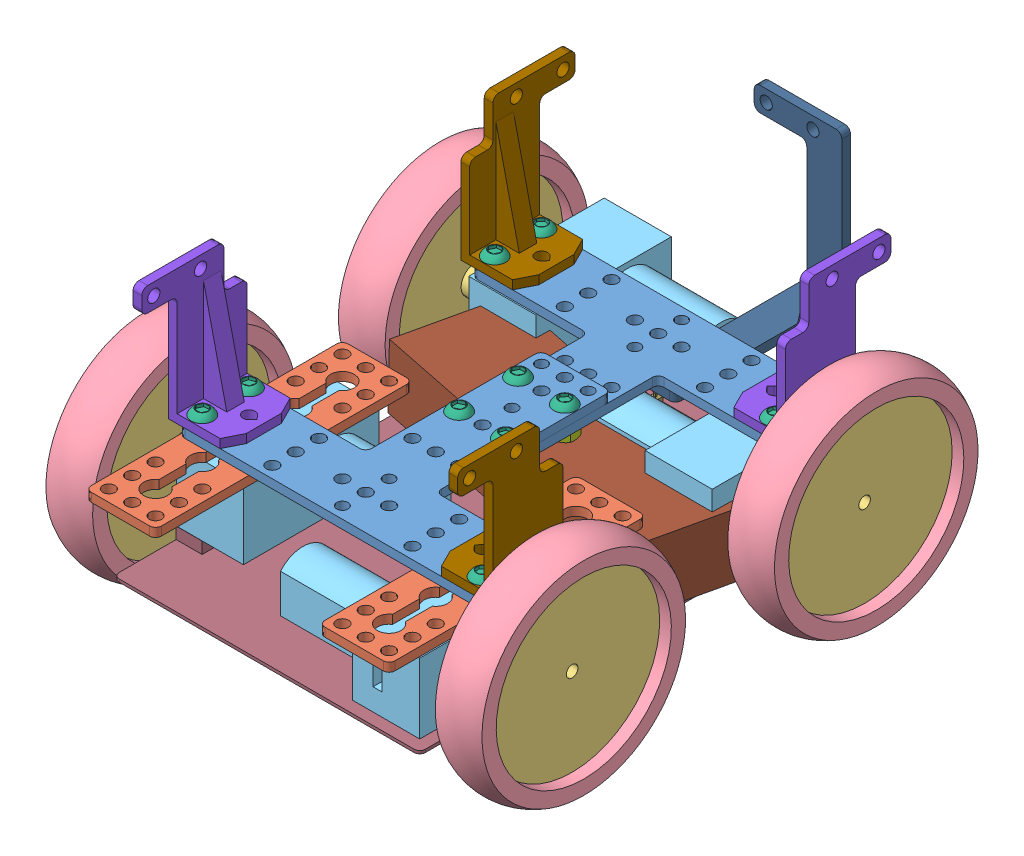
SolidWorks assembly robot_asm, configuration Default. Lengths in mm.
Overall size (148.9 115.69 200.04).
51 component instances, 19 part files, 120 mates.
Components (placement in the parent):
- maze-2: maze [Default] at origin size (310 310 586.12) (hidden)
  - maze_cell-1: maze_cell [Default] at origin size (310 310 310)
  - maze_slope-1: maze_slope [Default] at (0 -9.0631 4.2262) x (0 0.422618 0.906308) z (-1 0 0) size (300 10 300)
- T-bracket-1: T-bracket [Default] at (150 49 -175.7799) size (104 3 84)
- T-bracket-2: T-bracket [Default] at (150 52 -99.5799) x (-1 0 0) z (0 0 -1) size (104 3 84)
- bracket-1: bracket [Default] at (98 49 -43.5799) size (24 3 88)
- bracket-3: bracket [Default] at (178 49 -43.5799) size (24 3 88)
- wheels-1: wheels [Default] at (87.55 37 -87.3299) x (0 0 1) z (-1 0 0) size (67.99 67.99 16)
- wheels-2: wheels [Default] at (87.55 37 -187.5299) x (0 0 -1) z (-1 0 0) size (67.99 67.99 16)
- wheels-4: wheels [Default] at (212.45 37 -188.0299) x (0 0 1) z (1 0 0) size (67.99 67.99 16)
- wheels-6: wheels [Default] at (212.45 37 -87.8299) x (0 0 1) z (1 0 0) size (67.99 67.99 16)
- tire-1: tire [Default] at (216.45 37 -87.8299) x (1 0 0) z (0 0.015779 -0.999876) size (16 74 74)
- tire-2: tire [Default] at (216.45 37 -188.0299) x (1 0 0) z (0 0.008537 -0.999964) size (16 74 74)
- tire-4: tire [Default] at (83.55 37 -187.5299) x (-1 0 0) z (0 -0.999272 0.038138) size (16 74 74)
- tire-6: tire [Default] at (83.55 37 -87.3299) x (-1 0 0) z (0 -0.815244 0.579117) size (16 74 74)
- encoder_motor-1: encoder_motor [Default] at (97.55 37 -221.7299) x (1 0 0) z (0 -1 0) size (64 46.4 24)
- encoder_motor-2: encoder_motor [Default] at (202.45 37 -153.8299) x (-1 0 0) z (0 -1 0) size (64 46.4 24)
- encoder_motor-5: encoder_motor [Default] at (97.55 37 -121.5299) x (1 0 0) z (0 -1 0) size (64 46.4 24)
- encoder_motor-7: encoder_motor [Default] at (202.45 37 -53.6299) x (-1 0 0) z (0 -1 0) size (64 46.4 24)
- auriga_board-1: auriga_board [Default] at (150 55 -228.2799) x (-1 0 0) z (0 0 -1) size (88.1 25.8 109.5) (hidden)
- raspberrypi_4-1: raspberrypi_4 [Default] at (181.9914 89.0117 -123.3645) x (0.017452 0 -0.999848) z (0.999848 0 0.017452) size (88 17.5 57.5) (hidden)
- bigscrew-6: bigscrew [Default] at (158 45 -147.7799) x (0.646317 0 -0.763069) z (0.763069 0 0.646317) size (7.5 12 7.5)
- bigscrew-8: bigscrew [Default] at (142 45 -147.7799) x (0.458424 0 -0.888734) z (0.888734 0 0.458424) size (7.5 12 7.5)
- bigscrew-10: bigscrew [Default] at (158 45 -127.5799) x (0.282723 0 -0.959201) z (0.959201 0 0.282723) size (7.5 12 7.5)
- bigscrew-11: bigscrew [Default] at (142 45 -127.5799) x (0.069298 0 -0.997596) z (0.997596 0 0.069298) size (7.5 12 7.5)
- bigscrew-12: bigscrew [Default] at (198 48 -79.5799) x (-0.166501 0 -0.986041) z (0.986041 0 -0.166501) size (7.5 12 7.5)
- bigscrew-13: bigscrew [Default] at (198 48 -95.5799) x (-0.397145 0 -0.917756) z (0.917756 0 -0.397145) size (7.5 12 7.5)
- bigscrew-14: bigscrew [Default] at (102 48 -79.5799) x (-0.593123 0 -0.805112) z (0.805112 0 -0.593123) size (7.5 12 7.5)
- bigscrew-15: bigscrew [Default] at (102 48 -95.5799) x (-0.736724 0 -0.676194) z (0.676194 0 -0.736724) size (7.5 12 7.5)
- nut-1: nut [Default] at (158 47.5 -127.5799) x (0.999863 0 0.016576) z (-0.016576 0 0.999863) size (8.21 3.51 7.16)
- nut-2: nut [Default] at (142 47.5 -127.5799) x (0.985071 0 -0.17215) z (0.17215 0 0.985071) size (8.21 3.51 7.16)
- nut-3: nut [Default] at (142 47.5 -147.7799) x (0.924799 0 -0.380457) z (0.380457 0 0.924799) size (8.21 3.51 7.16)
- nut-4: nut [Default] at (158 47.5 -147.7799) x (0.809836 0 -0.586657) z (0.586657 0 0.809836) size (8.21 3.51 7.16)
- bigscrew-20: bigscrew [Default] at (102 45 -195.7799) x (-0.349342 0 -0.936995) z (0.936995 0 -0.349342) size (7.5 12 7.5)
- bigscrew-21: bigscrew [Default] at (102 45 -179.7799) x (-0.562985 0 -0.826467) z (0.826467 0 -0.562985) size (7.5 12 7.5)
- bigscrew-24: bigscrew [Default] at (198 45 -195.7799) x (-0.734222 0 -0.678909) z (0.678909 0 -0.734222) size (7.5 12 7.5)
- bigscrew-25: bigscrew [Default] at (198 45 -179.7799) x (-0.850955 0 -0.525238) z (0.525238 0 -0.850955) size (7.5 12 7.5)
- ultrasonic_bracket_left-1: ultrasonic_bracket_left [Default] at (97.4 55 -87.5799) x (0 0 -1) z (1 0 0) size (36.1 46.1 20.7)
- ultrasonic_bracket_right-1: ultrasonic_bracket_right [Default] at (202.6 55 -87.5799) x (0 0 -1) z (1 0 0) size (36.1 46.1 20.7)
- ultrasonic_bracket_right-4: ultrasonic_bracket_right [Default] at (97.4 52 -187.7799) x (0 0 1) z (-1 0 0) size (36.1 46.1 20.7)
- ultrasonic_bracket_left-2: ultrasonic_bracket_left [Default] at (202.6 52 -187.7799) x (0 0 1) z (-1 0 0) size (36.1 46.1 20.7)
- ultrasonic_bracket_front-1: ultrasonic_bracket_front [Default] at (161.9 46 -232.7799) size (30 52.1 60)
- ultrasonic_sensor-1: ultrasonic_sensor [Default] at (201.1 93 -75.5799) x (0 0 -1) z (0 -1 0) size (56 29.8 36) (hidden)
- ultrasonic_sensor-3: ultrasonic_sensor [Default] at (150 90 -231.2799) x (-1 0 0) z (0 -1 0) size (56 29.8 36) (hidden)
- ultrasonic_sensor-4: ultrasonic_sensor [Default] at (98.9 93 -75.5799) x (0 0 1) z (0 -1 0) size (56 29.8 36) (hidden)
- ultrasonic_sensor-7: ultrasonic_sensor [Default] at (98.9 90 -199.7799) x (0 0 1) z (0 -1 0) size (56 29.8 36) (hidden)
- ultrasonic_sensor-9: ultrasonic_sensor [Default] at (201.1 90 -199.7799) x (0 0 -1) z (0 -1 0) size (56 29.8 36) (hidden)
- battery-1: battery [Default] at (99.7426 20.6883 -166.1374) x (-0.199339 0.017452 0.979775) z (-0.979925 -0.000152 -0.199367) size (35 21.7 105)
- picamera-1: picamera [Default] at (104.6974 75.4836 -152.1545) x (-0.008727 0 0.999962) z (-0.008726 -0.999962 -0.000076) size (361.94 309 272.17) (hidden)
- coloursensor-1: coloursensor [Default] at (140.094 21 -197.6859) x (0 0 1) z (-1 0 0) size (20.32 7.03 26.3)
- undercover-1: undercover [Default] at (202.45 25 -153.8299) x (-1 0 0) z (0 -1 0) size (104.9 168.1 5)
Mates (geometry in assembly coordinates):
- Concentric1: concentric aligned: cylinder of T-bracket-1 through (142 49 -147.7799) axis (0 1 0) radius 2.1; cylinder of T-bracket-2 through (142 52 -147.7799) axis (0 1 0) radius 2.1
- Concentric2: concentric aligned: cylinder of T-bracket-1 through (158 49 -127.5799) axis (0 1 0) radius 2.1; cylinder of T-bracket-2 through (158 52 -127.5799) axis (0 1 0) radius 2.1
- Coincident1: coincident anti-aligned: plane of T-bracket-1 through (150 52 -175.7799) normal (0 1 0); plane of T-bracket-2 through (150 52 -99.5799) normal (0 -1 0)
- Concentric5: concentric aligned: cylinder of T-bracket-1 through (102 49 -195.7799) axis (0 1 0) radius 2.1; cylinder of encoder_motor-1 through (102 43.5 -195.7799) axis (0 1 0) radius 1.95
- Concentric6: concentric aligned: cylinder of T-bracket-1 through (102 49 -179.7799) axis (0 1 0) radius 2.1; cylinder of encoder_motor-1 through (102 43.5 -179.7799) axis (0 1 0) radius 1.95
- Coincident3: coincident anti-aligned: plane of T-bracket-1 through (150 49 -175.7799) normal (0 -1 0); plane of encoder_motor-1 through (97.55 49 -221.7299) normal (0 1 0)
- Concentric7: concentric aligned: cylinder of T-bracket-1 through (198 49 -179.7799) axis (0 1 0) radius 2.1; cylinder of encoder_motor-2 through (198 43.5 -179.7799) axis (0 1 0) radius 1.95
- Concentric8: concentric aligned: cylinder of T-bracket-1 through (198 49 -195.7799) axis (0 1 0) radius 2.1; cylinder of encoder_motor-2 through (198 43.5 -195.7799) axis (0 1 0) radius 1.95
- Coincident4: coincident anti-aligned: plane of T-bracket-1 through (150 49 -175.7799) normal (0 -1 0); plane of encoder_motor-2 through (202.45 49 -153.8299) normal (0 1 0)
- Concentric11: concentric aligned: cylinder of T-bracket-2 through (102 52 -95.5799) axis (0 1 0) radius 2.1; cylinder of bracket-1 through (102 49 -95.5799) axis (0 1 0) radius 2.1
- Concentric12: concentric aligned: cylinder of T-bracket-2 through (102 52 -79.5799) axis (0 1 0) radius 2.1; cylinder of bracket-1 through (102 49 -79.5799) axis (0 1 0) radius 2.1
- Coincident6: coincident anti-aligned: plane of T-bracket-2 through (150 52 -99.5799) normal (0 -1 0); plane of bracket-1 through (98 52 -43.5799) normal (0 1 0)
- Concentric13: concentric aligned: cylinder of T-bracket-2 through (198 52 -95.5799) axis (0 1 0) radius 2.1; cylinder of bracket-3 through (198 49 -95.5799) axis (0 1 0) radius 2.1
- Concentric14: concentric aligned: cylinder of T-bracket-2 through (198 52 -79.5799) axis (0 1 0) radius 2.1; cylinder of bracket-3 through (198 49 -79.5799) axis (0 1 0) radius 2.1
- Coincident7: coincident anti-aligned: plane of T-bracket-2 through (150 52 -99.5799) normal (0 -1 0); plane of bracket-3 through (178 52 -43.5799) normal (0 1 0)
- Concentric15: concentric aligned: cylinder of T-bracket-2 through (102 52 -95.5799) axis (0 1 0) radius 2.1; cylinder of encoder_motor-5 through (102 43.5 -95.5799) axis (0 1 0) radius 1.95
- Concentric16: concentric aligned: cylinder of T-bracket-2 through (102 52 -79.5799) axis (0 1 0) radius 2.1; cylinder of encoder_motor-5 through (102 43.5 -79.5799) axis (0 1 0) radius 1.95
- Coincident8: coincident anti-aligned: plane of bracket-1 through (98 49 -43.5799) normal (0 -1 0); plane of encoder_motor-5 through (97.55 49 -121.5299) normal (0 1 0)
- Concentric17: concentric aligned: cylinder of T-bracket-2 through (198 52 -79.5799) axis (0 1 0) radius 2.1; cylinder of encoder_motor-7 through (198 43.5 -79.5799) axis (0 1 0) radius 1.95
- Concentric18: concentric aligned: cylinder of T-bracket-2 through (198 52 -95.5799) axis (0 1 0) radius 2.1; cylinder of encoder_motor-7 through (198 43.5 -95.5799) axis (0 1 0) radius 1.95
- Coincident9: coincident anti-aligned: plane of bracket-3 through (178 49 -43.5799) normal (0 -1 0); plane of encoder_motor-7 through (202.45 49 -53.6299) normal (0 1 0)
- Concentric19: concentric aligned: cylinder of encoder_motor-5 through (88.55 37 -87.3299) axis (1 0 0) radius 2.7; cylinder of wheels-1 through (81.1435 37 -87.3299) axis (1 0 0) radius 2.85
- Parallel1: parallel anti-aligned: plane of encoder_motor-5 through (88.55 35.25 -75.1299) normal (0 -1 0); plane of wheels-1 through (81.1435 35.05 -85.2514) normal (0 1 0)
- Coincident11: coincident anti-aligned: plane of encoder_motor-5 through (95.55 35.25 -75.1299) normal (-1 0 0); plane of wheels-1 through (95.55 37 -87.3299) normal (1 0 0)
- Concentric20: concentric aligned: cylinder of encoder_motor-1 through (88.55 37 -187.5299) axis (1 0 0) radius 2.7; cylinder of wheels-2 through (81.1435 37 -187.5299) axis (1 0 0) radius 2.85
- Parallel2: parallel anti-aligned: plane of encoder_motor-1 through (88.55 38.75 -175.3299) normal (0 1 0); plane of wheels-2 through (81.1435 38.95 -189.6084) normal (0 -1 0)
- Coincident12: coincident anti-aligned: plane of encoder_motor-1 through (95.55 38.75 -175.3299) normal (-1 0 0); plane of wheels-2 through (95.55 37 -187.5299) normal (1 0 0)
- Concentric21: concentric aligned: cylinder of encoder_motor-2 through (211.45 37 -188.0299) axis (-1 0 0) radius 2.7; cylinder of wheels-4 through (218.8565 37 -188.0299) axis (-1 0 0) radius 2.85
- Parallel3: parallel anti-aligned: plane of encoder_motor-2 through (211.45 38.75 -200.2299) normal (0 1 0); plane of wheels-4 through (218.8565 38.95 -185.9514) normal (0 -1 0)
- Coincident13: coincident anti-aligned: plane of encoder_motor-2 through (204.45 38.75 -200.2299) normal (1 0 0); plane of wheels-4 through (204.45 37 -188.0299) normal (-1 0 0)
- Concentric22: concentric aligned: cylinder of encoder_motor-7 through (211.45 37 -87.8299) axis (-1 0 0) radius 2.7; cylinder of wheels-6 through (218.8565 37 -87.8299) axis (-1 0 0) radius 2.85
- Parallel4: parallel anti-aligned: plane of encoder_motor-7 through (211.45 38.75 -100.0299) normal (0 1 0); plane of wheels-6 through (218.8565 38.95 -85.7514) normal (0 -1 0)
- Coincident14: coincident anti-aligned: plane of encoder_motor-7 through (204.45 38.75 -100.0299) normal (1 0 0); plane of wheels-6 through (204.45 37 -87.8299) normal (-1 0 0)
- Concentric23: concentric aligned: cylinder of wheels-6 through (220.45 37 -87.8299) axis (-1 0 0) radius 34; cylinder of tire-1 through (-474.0168 37 -87.8299) axis (-1 0 0) radius 33
- Coincident16: coincident anti-aligned: plane of wheels-6 through (212.45 37 -87.8299) normal (-1 0 0); plane of tire-1 through (212.45 4.0041 -88.3506) normal (1 0 0)
- Concentric24: concentric aligned: cylinder of wheels-4 through (220.45 37 -188.0299) axis (-1 0 0) radius 34; cylinder of tire-2 through (-474.0168 37 -188.0299) axis (-1 0 0) radius 33
- Coincident17: coincident anti-aligned: plane of wheels-4 through (212.45 37 -188.0299) normal (-1 0 0); plane of tire-2 through (212.45 4.0012 -188.3116) normal (1 0 0)
- Concentric25: concentric aligned: cylinder of wheels-2 through (79.55 37 -187.5299) axis (1 0 0) radius 34; cylinder of tire-4 through (774.0168 37 -187.5299) axis (1 0 0) radius 33
- Coincident18: coincident anti-aligned: plane of wheels-2 through (87.55 37 -187.5299) normal (1 0 0); plane of tire-4 through (87.55 35.7414 -220.5059) normal (-1 0 0)
- Concentric26: concentric aligned: cylinder of wheels-1 through (79.55 37 -87.3299) axis (1 0 0) radius 34; cylinder of tire-6 through (774.0168 37 -87.3299) axis (1 0 0) radius 33
- Coincident19: coincident anti-aligned: plane of wheels-1 through (87.55 37 -87.3299) normal (1 0 0); plane of tire-6 through (87.55 17.8891 -114.233) normal (-1 0 0)
- Coincident25: coincident anti-aligned: plane of T-bracket-2 through (150 55 -99.5799) normal (0 1 0); plane of bigscrew-6 through (159.2926 55 -149.306) normal (0 -1 0)
- Concentric31: concentric anti-aligned: cylinder of T-bracket-2 through (158 52 -147.7799) axis (0 1 0) radius 2.1; cylinder of bigscrew-6 through (158 -265.2059 -147.7799) axis (0 -1 0) radius 2
- Concentric32: concentric anti-aligned: cylinder of T-bracket-2 through (142 52 -147.7799) axis (0 1 0) radius 2.1; cylinder of bigscrew-8 through (142 -265.2059 -147.7799) axis (0 -1 0) radius 2
- Coincident27: coincident anti-aligned: plane of T-bracket-2 through (150 55 -99.5799) normal (0 1 0); plane of bigscrew-8 through (142.9168 55 -149.5574) normal (0 -1 0)
- Coincident28: coincident anti-aligned: plane of T-bracket-2 through (150 55 -99.5799) normal (0 1 0); plane of bigscrew-10 through (158.5654 55 -129.4983) normal (0 -1 0)
- Concentric33: concentric anti-aligned: cylinder of T-bracket-2 through (158 52 -127.5799) axis (0 1 0) radius 2.1; cylinder of bigscrew-10 through (158 -265.2059 -127.5799) axis (0 -1 0) radius 2
- Coincident29: coincident anti-aligned: plane of T-bracket-2 through (150 55 -99.5799) normal (0 1 0); plane of bigscrew-11 through (142.1386 55 -129.5751) normal (0 -1 0)
- Concentric34: concentric anti-aligned: cylinder of T-bracket-2 through (142 52 -127.5799) axis (0 1 0) radius 2.1; cylinder of bigscrew-11 through (142 -265.2059 -127.5799) axis (0 -1 0) radius 2
- Coincident30: coincident anti-aligned: plane of ultrasonic_bracket_right-1 through (202.6 58 -87.5799) normal (0 1 0); plane of bigscrew-12 through (197.667 58 -81.552) normal (0 -1 0)
- Concentric35: concentric anti-aligned: cylinder of T-bracket-2 through (198 52 -79.5799) axis (0 1 0) radius 2.1; cylinder of bigscrew-12 through (198 -262.2059 -79.5799) axis (0 -1 0) radius 2
- Coincident31: coincident anti-aligned: plane of ultrasonic_bracket_right-1 through (202.6 58 -87.5799) normal (0 1 0); plane of bigscrew-13 through (197.2057 58 -97.4154) normal (0 -1 0)
- Concentric36: concentric anti-aligned: cylinder of T-bracket-2 through (198 52 -95.5799) axis (0 1 0) radius 2.1; cylinder of bigscrew-13 through (198 -262.2059 -95.5799) axis (0 -1 0) radius 2
- Concentric37: concentric anti-aligned: cylinder of T-bracket-2 through (102 52 -79.5799) axis (0 1 0) radius 2.1; cylinder of bigscrew-14 through (102 -262.2059 -79.5799) axis (0 -1 0) radius 2
- Concentric38: concentric anti-aligned: cylinder of T-bracket-2 through (102 52 -95.5799) axis (0 1 0) radius 2.1; cylinder of bigscrew-15 through (102 -262.2059 -95.5799) axis (0 -1 0) radius 2
- Concentric39: concentric aligned: cylinder of bigscrew-10 through (158 -265.2059 -127.5799) axis (0 -1 0) radius 2; cylinder of nut-1 through (158 49 -127.5799) axis (0 -1 0) radius 2
- Coincident35: coincident anti-aligned: plane of T-bracket-1 through (150 49 -175.7799) normal (0 -1 0); plane of nut-1 through (158 49 -127.5799) normal (0 1 0)
- Coincident36: coincident anti-aligned: plane of T-bracket-1 through (150 49 -175.7799) normal (0 -1 0); plane of nut-2 through (142 49 -127.5799) normal (0 1 0)
- Concentric40: concentric aligned: cylinder of bigscrew-11 through (142 -265.2059 -127.5799) axis (0 -1 0) radius 2; cylinder of nut-2 through (142 49 -127.5799) axis (0 -1 0) radius 2
- Coincident37: coincident anti-aligned: plane of T-bracket-1 through (150 49 -175.7799) normal (0 -1 0); plane of nut-3 through (142 49 -147.7799) normal (0 1 0)
- Concentric41: concentric aligned: cylinder of bigscrew-8 through (142 -265.2059 -147.7799) axis (0 -1 0) radius 2; cylinder of nut-3 through (142 49 -147.7799) axis (0 -1 0) radius 2
- Coincident38: coincident anti-aligned: plane of T-bracket-1 through (150 49 -175.7799) normal (0 -1 0); plane of nut-4 through (158 49 -147.7799) normal (0 1 0)
- Concentric42: concentric aligned: cylinder of bigscrew-6 through (158 -265.2059 -147.7799) axis (0 -1 0) radius 2; cylinder of nut-4 through (158 49 -147.7799) axis (0 -1 0) radius 2
- Tangent1: tangent anti-aligned: torus of tire-4; plane of maze-2/maze_cell-1 through (0 0 0) normal (0 1 0)
- Tangent4: tangent anti-aligned: plane of maze-2/maze_slope-1 through (0 0 0) normal (0 0.906308 -0.422618); torus of tire-1
- Tangent6: tangent anti-aligned: plane of maze-2/maze_cell-1 through (0 0 0) normal (0 1 0); torus of tire-2
- Tangent7: tangent anti-aligned: plane of maze-2/maze_slope-1 through (0 0 0) normal (0 0.906308 -0.422618); torus of tire-6
- Tangent8: tangent anti-aligned: plane of maze-2/maze_cell-1 through (0 0 0) normal (0 1 0); torus of tire-1
- Parallel7: parallel aligned: plane of maze-2/maze_cell-1 through (300 -10 0) normal (1 0 0); plane of wheels-6 through (220.45 37 -87.8299) normal (1 0 0)
- Distance1: distance = 150 mm: cylinder of T-bracket-2 through (150 52 -87.5799) axis (0 1 0) radius 2.1; plane of maze-2/maze_cell-1 through (0 0 0) normal (1 0 0)
- Concentric43: concentric anti-aligned: cylinder of T-bracket-2 through (102 52 -79.5799) axis (0 1 0) radius 2.1; cylinder of ultrasonic_bracket_left-1 through (102 58 -79.5799) axis (0 -1 0) radius 2.1
- Concentric44: concentric anti-aligned: cylinder of T-bracket-2 through (102 52 -95.5799) axis (0 1 0) radius 2.1; cylinder of ultrasonic_bracket_left-1 through (102 58 -95.5799) axis (0 -1 0) radius 2.1
- Coincident39: coincident anti-aligned: plane of T-bracket-2 through (150 55 -99.5799) normal (0 1 0); plane of ultrasonic_bracket_left-1 through (97.4 55 -87.5799) normal (0 -1 0)
- Coincident40: coincident anti-aligned: plane of bigscrew-14 through (100.8138 58 -81.1901) normal (0 -1 0); plane of ultrasonic_bracket_left-1 through (97.4 58 -87.5799) normal (0 1 0)
- Coincident41: coincident anti-aligned: plane of bigscrew-15 through (100.5266 58 -96.9323) normal (0 -1 0); plane of ultrasonic_bracket_left-1 through (97.4 58 -87.5799) normal (0 1 0)
- Concentric45: concentric aligned: cylinder of ultrasonic_sensor-4 through (97.4 97 -83.5799) axis (1 0 0) radius 2.1; cylinder of ultrasonic_bracket_left-1 through (94.4 97 -83.5799) axis (1 0 0) radius 2.1
- Concentric46: concentric aligned: cylinder of ultrasonic_sensor-4 through (97.4 97 -67.5799) axis (1 0 0) radius 2.1; cylinder of ultrasonic_bracket_left-1 through (94.4 97 -67.5799) axis (1 0 0) radius 2.1
- Coincident43: coincident anti-aligned: plane of ultrasonic_sensor-4 through (97.4 93 -75.5799) normal (-1 0 0); plane of ultrasonic_bracket_left-1 through (97.4 55 -87.5799) normal (1 0 0)
- Concentric47: concentric anti-aligned: cylinder of T-bracket-2 through (198 52 -95.5799) axis (0 1 0) radius 2.1; cylinder of ultrasonic_bracket_right-1 through (198 58 -95.5799) axis (0 -1 0) radius 2.1
- Concentric48: concentric anti-aligned: cylinder of T-bracket-2 through (198 52 -79.5799) axis (0 1 0) radius 2.1; cylinder of ultrasonic_bracket_right-1 through (198 58 -79.5799) axis (0 -1 0) radius 2.1
- Coincident45: coincident anti-aligned: plane of T-bracket-2 through (150 55 -99.5799) normal (0 1 0); plane of ultrasonic_bracket_right-1 through (202.6 55 -87.5799) normal (0 -1 0)
- Concentric49: concentric aligned: cylinder of ultrasonic_sensor-1 through (202.6 97 -83.5799) axis (-1 0 0) radius 2.1; cylinder of ultrasonic_bracket_right-1 through (205.6 97 -83.5799) axis (-1 0 0) radius 2.1
- Concentric50: concentric aligned: cylinder of ultrasonic_sensor-1 through (202.6 97 -67.5799) axis (-1 0 0) radius 2.1; cylinder of ultrasonic_bracket_right-1 through (205.6 97 -67.5799) axis (-1 0 0) radius 2.1
- Coincident46: coincident anti-aligned: plane of ultrasonic_sensor-1 through (202.6 93 -75.5799) normal (1 0 0); plane of ultrasonic_bracket_right-1 through (202.6 55 -87.5799) normal (-1 0 0)
- Coincident54: coincident anti-aligned: plane of ultrasonic_bracket_right-4 through (97.4 55 -187.7799) normal (0 1 0); plane of bigscrew-20 through (101.3013 55 -197.6539) normal (0 -1 0)
- Coincident55: coincident anti-aligned: plane of ultrasonic_bracket_right-4 through (97.4 55 -187.7799) normal (0 1 0); plane of bigscrew-21 through (100.874 55 -181.4328) normal (0 -1 0)
- Concentric61: concentric aligned: cylinder of ultrasonic_bracket_right-4 through (94.4 94 -191.7799) axis (1 0 0) radius 2.1; cylinder of ultrasonic_sensor-7 through (97.4 94 -191.7799) axis (1 0 0) radius 2.1
- Concentric62: concentric aligned: cylinder of ultrasonic_bracket_right-4 through (94.4 94 -207.7799) axis (1 0 0) radius 2.1; cylinder of ultrasonic_sensor-7 through (97.4 94 -207.7799) axis (1 0 0) radius 2.1
- Coincident56: coincident anti-aligned: plane of ultrasonic_bracket_right-4 through (97.4 52 -187.7799) normal (1 0 0); plane of ultrasonic_sensor-7 through (97.4 90 -199.7799) normal (-1 0 0)
- Concentric63: concentric anti-aligned: cylinder of T-bracket-1 through (102 49 -195.7799) axis (0 1 0) radius 2.1; cylinder of bigscrew-20 through (102 -265.2059 -195.7799) axis (0 -1 0) radius 2
- Concentric64: concentric anti-aligned: cylinder of T-bracket-1 through (102 49 -179.7799) axis (0 1 0) radius 2.1; cylinder of bigscrew-21 through (102 -265.2059 -179.7799) axis (0 -1 0) radius 2
- Concentric65: concentric anti-aligned: cylinder of T-bracket-1 through (102 49 -179.7799) axis (0 1 0) radius 2.1; cylinder of ultrasonic_bracket_right-4 through (102 55 -179.7799) axis (0 -1 0) radius 2.1
- Concentric66: concentric anti-aligned: cylinder of T-bracket-1 through (102 49 -195.7799) axis (0 1 0) radius 2.1; cylinder of ultrasonic_bracket_right-4 through (102 55 -195.7799) axis (0 -1 0) radius 2.1
- Coincident57: coincident anti-aligned: plane of T-bracket-1 through (150 52 -175.7799) normal (0 1 0); plane of ultrasonic_bracket_right-4 through (97.4 52 -187.7799) normal (0 -1 0)
- Coincident61: coincident anti-aligned: plane of ultrasonic_bracket_left-2 through (202.6 55 -187.7799) normal (0 1 0); plane of bigscrew-24 through (196.5316 55 -197.1377) normal (0 -1 0)
- Coincident62: coincident anti-aligned: plane of ultrasonic_bracket_left-2 through (202.6 55 -187.7799) normal (0 1 0); plane of bigscrew-25 through (196.2981 55 -180.8304) normal (0 -1 0)
- Concentric69: concentric aligned: cylinder of ultrasonic_bracket_left-2 through (205.6 94 -191.7799) axis (-1 0 0) radius 2.1; cylinder of ultrasonic_sensor-9 through (202.6 94 -191.7799) axis (-1 0 0) radius 2.1
- Concentric70: concentric aligned: cylinder of ultrasonic_bracket_left-2 through (205.6 94 -207.7799) axis (-1 0 0) radius 2.1; cylinder of ultrasonic_sensor-9 through (202.6 94 -207.7799) axis (-1 0 0) radius 2.1
- Coincident63: coincident anti-aligned: plane of ultrasonic_bracket_left-2 through (202.6 52 -187.7799) normal (-1 0 0); plane of ultrasonic_sensor-9 through (202.6 90 -199.7799) normal (1 0 0)
- Concentric71: concentric anti-aligned: cylinder of T-bracket-1 through (198 49 -195.7799) axis (0 1 0) radius 2.1; cylinder of bigscrew-24 through (198 -265.2059 -195.7799) axis (0 -1 0) radius 2
- Concentric72: concentric anti-aligned: cylinder of T-bracket-1 through (198 49 -179.7799) axis (0 1 0) radius 2.1; cylinder of bigscrew-25 through (198 -265.2059 -179.7799) axis (0 -1 0) radius 2
- Concentric73: concentric anti-aligned: cylinder of T-bracket-1 through (198 49 -195.7799) axis (0 1 0) radius 2.1; cylinder of ultrasonic_bracket_left-2 through (198 55 -195.7799) axis (0 -1 0) radius 2.1
- Concentric74: concentric anti-aligned: cylinder of T-bracket-1 through (198 49 -179.7799) axis (0 1 0) radius 2.1; cylinder of ultrasonic_bracket_left-2 through (198 55 -179.7799) axis (0 -1 0) radius 2.1
- Coincident64: coincident anti-aligned: plane of T-bracket-1 through (150 52 -175.7799) normal (0 1 0); plane of ultrasonic_bracket_left-2 through (202.6 52 -187.7799) normal (0 -1 0)
- Concentric75: concentric anti-aligned: cylinder of auriga_board-1 through (190 55 -187.7799) axis (0 1 0) radius 2.1; cylinder of ultrasonic_bracket_left-2 through (190 55 -187.7799) axis (0 -1 0) radius 2.1
- Concentric76: concentric anti-aligned: cylinder of auriga_board-1 through (110 55 -187.7799) axis (0 1 0) radius 2.1; cylinder of ultrasonic_bracket_right-4 through (110 55 -187.7799) axis (0 -1 0) radius 2.1
- Coincident65: coincident anti-aligned: plane of auriga_board-1 through (150 55 -228.2799) normal (0 -1 0); plane of ultrasonic_bracket_right-4 through (97.4 55 -187.7799) normal (0 1 0)
- Concentric77: concentric anti-aligned: cylinder of T-bracket-1 through (150 49 -179.7799) axis (0 1 0) radius 1.95; cylinder of ultrasonic_bracket_front-1 through (150 49 -179.7799) axis (0 -1 0) radius 2.1
- Concentric78: concentric anti-aligned: cylinder of T-bracket-1 through (150 49 -195.7799) axis (0 1 0) radius 1.95; cylinder of ultrasonic_bracket_front-1 through (150 49 -195.7799) axis (0 -1 0) radius 2.1
- Concentric79: concentric aligned: cylinder of ultrasonic_sensor-3 through (158 94 -232.7799) axis (0 0 1) radius 2.1; cylinder of ultrasonic_bracket_front-1 through (158 94 -235.7799) axis (0 0 1) radius 2.1
- Concentric80: concentric aligned: cylinder of ultrasonic_sensor-3 through (142 94 -232.7799) axis (0 0 1) radius 2.1; cylinder of ultrasonic_bracket_front-1 through (142 94 -235.7799) axis (0 0 1) radius 2.1
- Coincident67: coincident anti-aligned: plane of ultrasonic_sensor-3 through (150 90 -232.7799) normal (0 0 -1); plane of ultrasonic_bracket_front-1 through (161.9 46 -232.7799) normal (0 0 1)
- Coincident68: coincident anti-aligned: plane of T-bracket-1 through (150 49 -175.7799) normal (0 -1 0); plane of ultrasonic_bracket_front-1 through (161.9 49 -232.7799) normal (0 1 0)
- InPlace1: in place: plane of ? through (202.45 25 -154.8771) normal (0 -1 0); plane of ? through (0 25 0) normal (0 -1 0); moOrthogonalPlaneRef_w of ? through (202.45 25 -154.8771) normal (0 -1 0); plane of ? through (0 25 0) normal (0 0 -1); plane of ? through (202.45 25 -154.8771) normal (0 -1 0); plane of ? through (0 25 0) normal (-1 0 0); plane of encoder_motor-2 through (202.45 25 -153.8299) normal (0 -1 0); unknown of undercover-1
- Coincident69: coincident aligned: plane of encoder_motor-2; plane of undercover-1
- Coincident70: coincident aligned: moOrthogonalPlaneRef_w of encoder_motor-2 through (202.45 25 -153.8299) normal (0 0 -1); plane of undercover-1 through (202.45 25 -153.8299) normal (0 0 -1)
- Coincident71: coincident anti-aligned: moOrthogonalPlaneRef_w of encoder_motor-2 through (202.45 25 -153.8299) normal (1 0 0); plane of undercover-1 through (202.45 25 -153.8299) normal (-1 0 0)
- Concentric81: concentric aligned: cylinder of coloursensor-1 through (157.789 22.65 -179.9059) axis (0 -1 0) radius 1.325; cylinder of undercover-1 through (157.789 25.001 -179.9059) axis (0 -1 0) radius 1.475
- Concentric82: concentric aligned: cylinder of coloursensor-1 through (157.789 22.65 -195.1459) axis (0 -1 0) radius 1.325; cylinder of undercover-1 through (157.789 25.001 -195.1459) axis (0 -1 0) radius 1.475
- Coincident76: coincident anti-aligned: plane of coloursensor-1 through (140.094 21 -197.6859) normal (0 -1 0); plane of undercover-1 through (202.45 21 -153.8299) normal (0 1 0)
